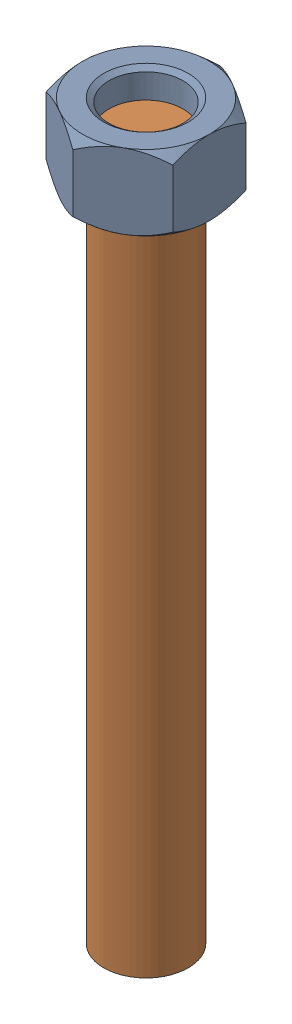
SolidWorks assembly 01-117-00-0, configuration Default. Lengths in mm.
Overall size (28.57 165.1 33).
2 component instances, 2 part files, 0 mates.
Components (placement in the parent):
- hex nut_ai(HNUT 0.7500-10-D-C)-1: hex nut_ai(HNUT 0.7500-10-D-C) [Default] at (0 165.1 0) x (1 0 0) z (0 1 0) size (28.57 33 16.89)
- TROD 0.7500-1x6.25-1: TROD 0.7500-1x6.25 [Default] at origin size (19.05 158.75 19.05)
